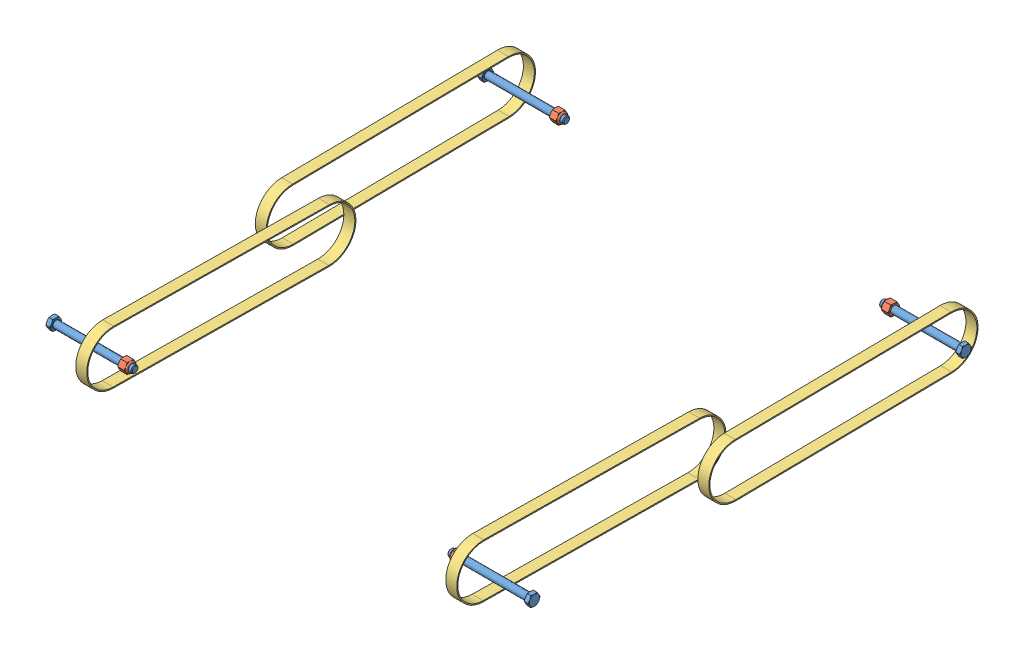
SolidWorks assembly Chassis, configuration Default. Lengths in mm.
Overall size (660.06 77.51 664.05).
20 component instances, 3 part files, 0 mates.
Components (placement in the parent):
- LONG CHASIS.STEP-1: LONG CHASIS.STEP [Default] at origin size (660.06 77.51 664.05)
  - AM14U5 Configurable Gearboxes_Long _TB Mini_6wD Churro Locations.STEP-1: AM14U5 Configurable Gearboxes_Long _TB Mini_6wD Churro Locations.STEP [Default] at origin (suppressed, hidden)
  - 2022 6 HiGrip with hub and double pulley.STEP-1: 2022 6 HiGrip with hub and double pulley.STEP [Default] at (-96.3242 -81.1238 258.7405) x (1 0 0) z (0 -0.377652 0.925948) (suppressed, hidden)
  - 2022 6 HiGrip with bearings, pulleys and spacers.STEP-1: 2022 6 HiGrip with bearings, pulleys and spacers.STEP [Default] at (-96.7941 92.575 150.502) x (1 0 0) z (0 -0.726066 -0.687625) (suppressed, hidden)
  - 2022 6 HiGrip with bearings, pulleys and spacers-1.STEP-1: 2022 6 HiGrip with bearings, pulleys and spacers-1.STEP [Default] at (-33.3809 -205.351 740.6027) x (-1 0 0) z (0 0.726066 -0.687625) (suppressed, hidden)
  - 2022 6 HiGrip with bearings, pulleys and spacers-2.STEP-1: 2022 6 HiGrip with bearings, pulleys and spacers-2.STEP [Default] at (-652.4191 -13.1296 558.5582) x (1 0 0) z (0 -0.726066 0.687625) (suppressed, hidden)
  - 2022 6 HiGrip with hub and double pulley-1.STEP-1: 2022 6 HiGrip with hub and double pulley-1.STEP [Default] at (-589.4758 -181.1047 503.8794) x (-1 0 0) z (0 0.377652 -0.925948) (suppressed, hidden)
  - 2022 6 HiGrip with bearings, pulleys and spacers-3.STEP-1: 2022 6 HiGrip with bearings, pulleys and spacers-3.STEP [Default] at (-589.0059 -99.6464 -31.5425) x (-1 0 0) z (0 0.726066 0.687625) (suppressed, hidden)
  - 375-16 x 4.25 Hex Bolt_HFBOLT 0.375-16x2.5x1-C.STEP-1: 375-16 x 4.25 Hex Bolt_HFBOLT 0.375-16x2.5x1-C.STEP [Default] at (-12.8778 -56.388 115.2866) x (-1 0 0) z (0 1 0) size (114.13 16.49 16.5)
  - 375-16 Lock Nut_91831A127.STEP-1: 375-16 Lock Nut_91831A127.STEP [Default] at (-111.125 -56.388 115.2866) x (0 0.5 -0.866025) z (0 0.866025 0.5) size (14.29 11.52 16.5)
  - 800-5M-15 v2.STEP-1: 800-5M-15 v2.STEP [Default] at (-32.8924 -59.9444 410.337) x (0 0.012053 -0.999927) z (0 0.999927 0.012053) size (368.15 15 73.08)
  - 800-5M-15 v2.STEP-2: 800-5M-15 v2.STEP [Default] at (-82.4477 -59.9444 410.337) x (0 0.012053 0.999927) z (0 -0.999927 0.012053) size (368.15 15 73.08)
  - 375-16 x 4.25 Hex Bolt_HFBOLT 0.375-16x2.5x1-C.STEP-2: 375-16 x 4.25 Hex Bolt_HFBOLT 0.375-16x2.5x1-C.STEP [Default] at (-12.8778 -56.388 705.3874) x (-1 0 0) z (0 -1 0) size (114.13 16.49 16.5)
  - 375-16 Lock Nut_91831A127.STEP-2: 375-16 Lock Nut_91831A127.STEP [Default] at (-111.125 -56.388 705.3874) x (0 -0.5 -0.866025) z (0 0.866025 -0.5) size (14.29 11.52 16.5)
  - 800-5M-15 v2.STEP-3: 800-5M-15 v2.STEP [Default] at (-603.3523 -59.9444 410.337) x (0 0.012053 0.999927) z (0 0.999927 -0.012053) size (368.15 15 73.08)
  - 375-16 x 4.25 Hex Bolt_HFBOLT 0.375-16x2.5x1-C.STEP-3: 375-16 x 4.25 Hex Bolt_HFBOLT 0.375-16x2.5x1-C.STEP [Default] at (-672.9222 -56.388 115.2866) x (1 0 0) z (0 -1 0) size (114.13 16.49 16.5)
  - 375-16 Lock Nut_91831A127.STEP-3: 375-16 Lock Nut_91831A127.STEP [Default] at (-574.675 -56.388 115.2866) x (0 -0.5 0.866025) z (0 0.866025 0.5) size (14.29 11.52 16.5)
  - 375-16 Lock Nut_91831A127.STEP-4: 375-16 Lock Nut_91831A127.STEP [Default] at (-574.675 -56.388 705.3874) x (0 0.5 0.866025) z (0 0.866025 -0.5) size (14.29 11.52 16.5)
  - 375-16 x 4.25 Hex Bolt_HFBOLT 0.375-16x2.5x1-C.STEP-4: 375-16 x 4.25 Hex Bolt_HFBOLT 0.375-16x2.5x1-C.STEP [Default] at (-672.9222 -56.388 705.3874) x (1 0 0) z (0 1 0) size (114.13 16.49 16.5)
  - 800-5M-15 v2.STEP-4: 800-5M-15 v2.STEP [Default] at (-652.9076 -59.9444 410.337) x (0 0.012053 -0.999927) z (0 -0.999927 -0.012053) size (368.15 15 73.08)
